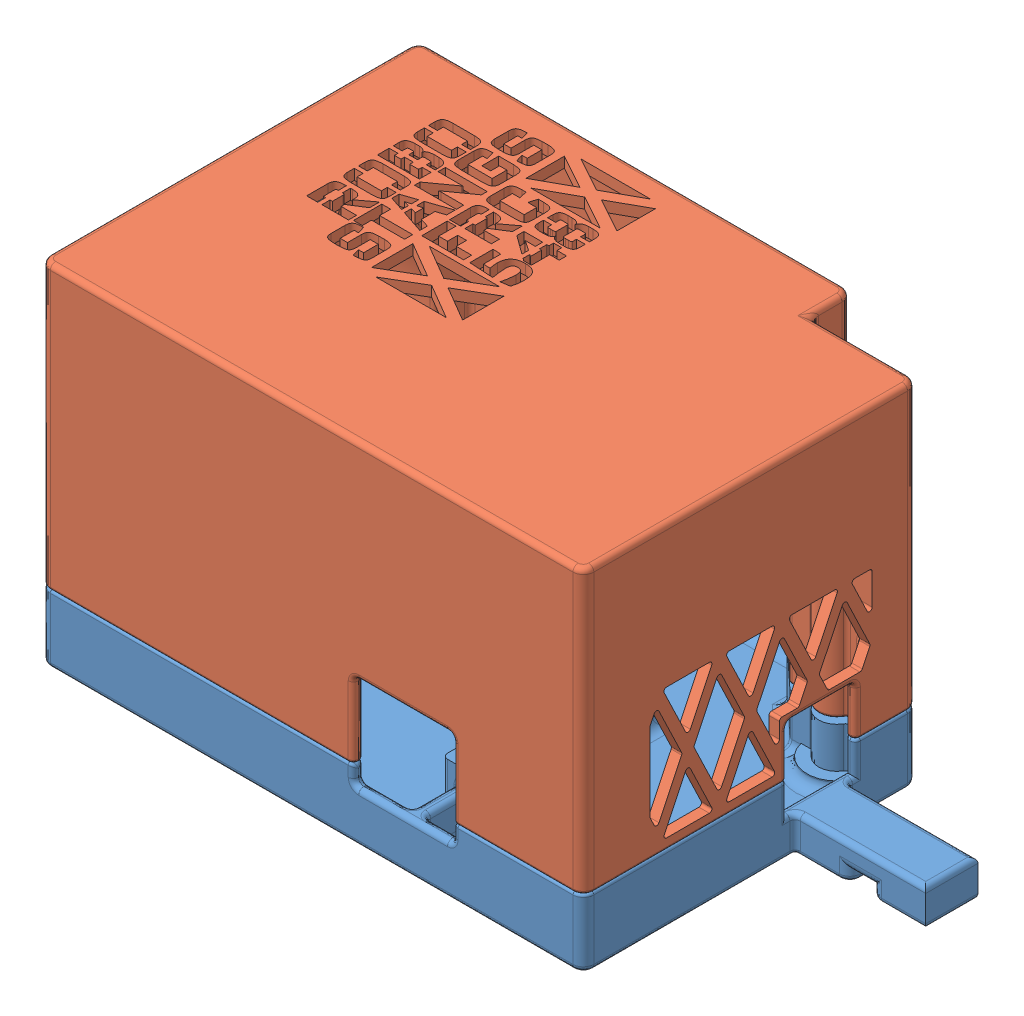
SolidWorks assembly main, configuration Default. Lengths in mm.
Overall size (129 67 72.5).
4 component instances, 4 part files, 11 mates.
Components (placement in the parent):
- stuff inside-1: stuff inside [Default] at origin size (117 60 92.5) (hidden)
- fan-1: fan [Default] at (-29 21 -26.2354) x (0 0 -1) z (1 0 0) size (73.31 73.31 25.79) (hidden)
- bottom-1: bottom [Default] x (-1 0 0) z (0 -1 0) size (129 72.5 13.02)
- top-1: top [Default] at (0 1 0) x (1 0 0) z (0 1 0) size (104 72.5 54)
Mates (geometry in assembly coordinates):
- Parallel1: parallel anti-aligned: plane of Part1^main-1 through (0 1 0) normal (-1 0 0); plane of fan-1 through (-29 284.1376 -180.1679) normal (1 0 0)
- Coincident2: coincident: plane of Part1^main-1 through (0 -9 0) normal (0 -1 0); line of fan-1 through (-29 -9 -51.2354) axis (0 0 1)
- Distance1: distance = 12 mm anti-aligned: plane of fan-1 through (-29 284.1376 -180.1679) normal (1 0 0); plane of Part1^main-1 through (-17 -9 0) normal (-1 0 0)
- InPlace1: in place: plane of stuff inside-1 through (0 0 0) normal (0 -1 0); plane of bottom-1 through (0 0 0) normal (0 -1 0); moOrthogonalPlaneRef_w of stuff inside-1 through (0 0 0) normal (0 -1 0); plane of bottom-1 through (0 0 0) normal (0 0 -1); plane of stuff inside-1 through (0 0 0) normal (0 -1 0); plane of bottom-1 through (0 0 0) normal (-1 0 0); plane of stuff inside-1 through (0 0 0) normal (0 -1 0); unknown of bottom-1
- Coincident3: coincident aligned: plane of ?; plane of bottom-1
- Coincident4: coincident aligned: moOrthogonalPlaneRef_w of Part1^main-1 through (0 0 0) normal (0 0 -1); plane of bottom-1 through (0 0 0) normal (0 0 -1)
- Coincident5: coincident anti-aligned: moOrthogonalPlaneRef_w of Part1^main-1 through (0 0 0) normal (1 0 0); plane of bottom-1 through (0 0 0) normal (-1 0 0)
- InPlace2: in place: plane of bottom-1 through (0 1 0) normal (0 1 0); plane of top-1 through (0 1 0) normal (0 1 0); plane of bottom-1 through (0 1 0) normal (0 1 0); plane of top-1 through (0 1 0) normal (0 0 -1); plane of bottom-1 through (0 1 0) normal (0 1 0); plane of top-1 through (0 1 0) normal (1 0 0); plane of bottom-1 through (0 1 0) normal (0 1 0); unknown of top-1
- Coincident6: coincident aligned: plane of bottom-1; plane of top-1
- Coincident7: coincident aligned: moOrthogonalPlaneRef_w of bottom-1 through (0 1 0) normal (0 0 -1); plane of top-1 through (0 1 0) normal (0 0 -1)
- Coincident8: coincident anti-aligned: moOrthogonalPlaneRef_w of bottom-1 through (0 1 0) normal (-1 0 0); plane of top-1 through (0 1 0) normal (1 0 0)
